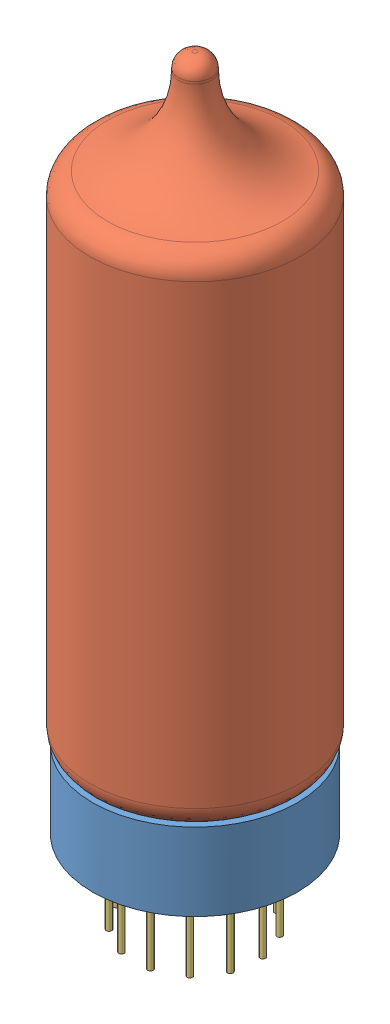
SolidWorks assembly IN-14, configuration Default. Lengths in mm.
Overall size (26.86 68.4 26.86).
3 component instances, 3 part files, 3 mates.
Components (placement in the parent):
- pcb_standoff-1: pcb_standoff [Default] at (7.1038 3.7208 15.749) size (18.5 7 18.5)
- tube_body-1: tube_body [Default] at (7.1038 10.3463 15.749) x (0.727659 0 0.685939) z (-0.685939 0 0.727659) size (19 54.5 19)
- tube_leads-1: tube_leads [Default] at (7.1038 8.4415 15.749) size (11.42 12 11.34)
Mates (geometry in assembly coordinates):
- Concentric1: concentric aligned: circle of pcb_standoff-1; circle of tube_leads-1
- Concentric2: concentric anti-aligned: circle of pcb_standoff-1; circle of tube_body-1
- Concentric3: concentric aligned: circle of pcb_standoff-1; circle of tube_leads-1
